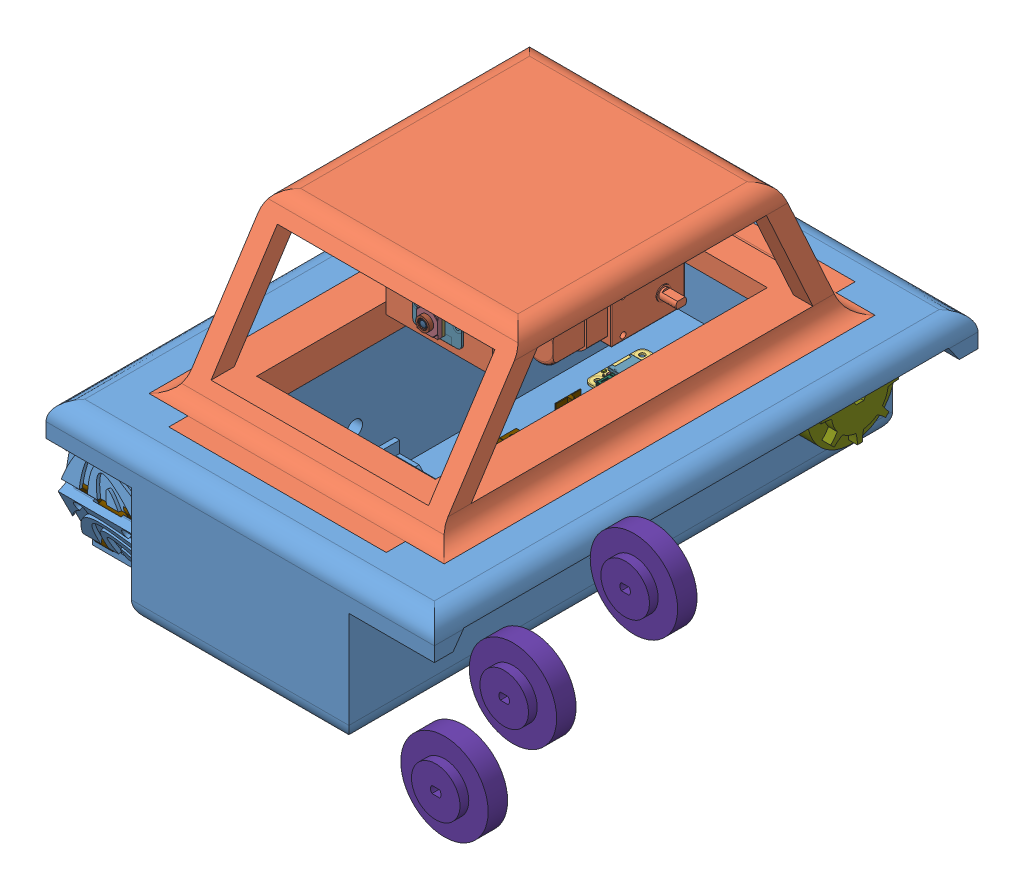
SolidWorks assembly AV_Comp_Mech_1_3_3_TotalAssembly, configuration Default. Lengths in mm.
Overall size (348.43 162.79 404.85).
170 component instances, 37 part files, 41 mates.
Components (placement in the parent):
- AV_Comp_Mech_1_3_2_3_Chassis3_Bot-1: AV_Comp_Mech_1_3_2_3_Chassis3_Bot [Default] at (109.8755 25.442 260.27) size (200 77.5 280)
- AV_Comp_Mech_1_3_1_3_Motors-1: AV_Comp_Mech_1_3_1_3_Motors [Default] at (82.6825 -10.6209 15.27) x (0 1 0) z (-1 0 0) size (22.6 65.53 37.6)
- AV_Comp_Mech_1_3_1_3_Motors-2: AV_Comp_Mech_1_3_1_3_Motors [Default] at (155.8685 -10.6209 15.27) x (0 1 0) z (-1 0 0) size (22.6 65.53 37.6)
- AV_Comp_Mech_1_3_1_2_Pi_Zero-1: AV_Comp_Mech_1_3_1_2_Pi_Zero [Default] at (157.9171 -59.1547 19.3835) size (65 4.45 31.23)
  - Raspberry_pizero_PCB-1: Raspberry_pizero_PCB [Default] at (-51.2564 20.0966 13.0542) size (65 1 30)
  - Micro USB_input_female (short)-SMT-1: Micro USB_input_female (short)-SMT [Default] at (-42.3564 22.3216 26.5042) size (7.98 2.94 5.43)
  - Micro USB_input_female (short)-SMT-2: Micro USB_input_female (short)-SMT [Default] at (-29.7564 22.3216 26.5042) size (7.98 2.94 5.43)
  - 0204 - Capacitor-1: 0204 - Capacitor [Default] at (-62.4121 21.3466 11.2398) size (1 0.5 0.6)
  - 0204 - Capacitor-2: 0204 - Capacitor [Default] at (-62.4121 21.3466 12.2528) size (1 0.5 0.6)
  - 0204 - Capacitor-3: 0204 - Capacitor [Default] at (-61.8122 21.3466 13.3136) size (1 0.5 0.6)
  - 0204 - Capacitor-4: 0204 - Capacitor [Default] at (-61.8122 21.3466 14.2646) size (1 0.5 0.6)
  - 0204 - Capacitor-5: 0204 - Capacitor [Default] at (-61.8122 21.3466 15.241) size (1 0.5 0.6)
  - 0204 - Capacitor-6: 0204 - Capacitor [Default] at (-61.8122 21.3466 16.2144) size (1 0.5 0.6)
  - 0204 - Capacitor-7: 0204 - Capacitor [Default] at (-61.8122 21.3466 17.2416) size (1 0.5 0.6)
  - 0204 - Capacitor-8: 0204 - Capacitor [Default] at (-62.5919 21.3466 20.9695) size (1 0.5 0.6)
  - 0204 - Capacitor-9: 0204 - Capacitor [Default] at (-62.5919 21.3466 21.919) size (1 0.5 0.6)
  - 0204 - Capacitor-10: 0204 - Capacitor [Default] at (-60.4584 21.3466 22.3712) x (0 0 1) z (-1 0 0) size (1 0.5 0.6)
  - 0204 - Capacitor-11: 0204 - Capacitor [Default] at (-60.0807 21.3466 22.3712) x (0 0 -1) z (1 0 0) size (1 0.5 0.6)
  - 0204 - Capacitor-12: 0204 - Capacitor [Default] at (-59.0466 21.3466 22.3712) x (0 0 -1) z (1 0 0) size (1 0.5 0.6)
  - 0204 - Capacitor-13: 0204 - Capacitor [Default] at (-52.6496 21.3466 22.316) x (0 0 1) z (-1 0 0) size (1 0.5 0.6)
  - 0204 - Capacitor-14: 0204 - Capacitor [Default] at (-52.25 21.3466 22.316) x (0 0 -1) z (1 0 0) size (1 0.5 0.6)
  - 0204 - Capacitor-15: 0204 - Capacitor [Default] at (-51.2398 21.3466 22.316) x (0 0 -1) z (1 0 0) size (1 0.5 0.6)
  - 0204 - Capacitor-16: 0204 - Capacitor [Default] at (-49.1841 21.3466 22.316) x (0 0 -1) z (1 0 0) size (1 0.5 0.6)
  - 0204 - Capacitor-17: 0204 - Capacitor [Default] at (-48.1448 21.3466 22.316) x (0 0 -1) z (1 0 0) size (1 0.5 0.6)
  - 0204 - Capacitor-18: 0204 - Capacitor [Default] at (-46.475 21.3466 21.113) size (1 0.5 0.6)
  - 0204 - Capacitor-19: 0204 - Capacitor [Default] at (-45.7322 21.3466 20.0663) size (1 0.5 0.6)
  - 0204 - Capacitor-20: 0204 - Capacitor [Default] at (-45.7322 21.3466 19.0675) size (1 0.5 0.6)
  - 0204 - Capacitor-21: 0204 - Capacitor [Default] at (-45.7322 21.3466 18.1249) size (1 0.5 0.6)
  - 0204 - Capacitor-22: 0204 - Capacitor [Default] at (-45.7322 21.3466 17.1095) size (1 0.5 0.6)
  - 0204 - Capacitor-23: 0204 - Capacitor [Default] at (-46.3457 21.3466 16.1412) size (1 0.5 0.6)
  - 0204 - Capacitor-24: 0204 - Capacitor [Default] at (-46.3457 21.3466 15.1229) size (1 0.5 0.6)
  - 0204 - Capacitor-25: 0204 - Capacitor [Default] at (-46.3457 21.3466 14.0197) size (1 0.5 0.6)
  - 0204 - Capacitor-26: 0204 - Capacitor [Default] at (-46.3457 21.3466 12.9589) size (1 0.5 0.6)
  - 0204 - Capacitor-27: 0204 - Capacitor [Default] at (-43.6156 21.3466 13.1418) size (1 0.5 0.6)
  - 0204 - Capacitor-28: 0204 - Capacitor [Default] at (-43.6156 21.3466 10.1424) size (1 0.5 0.6)
  - 0204 - Capacitor-29: 0204 - Capacitor [Default] at (-48.9117 21.3466 7.6917) size (1 0.5 0.6)
  - 0204 - Capacitor-30: 0204 - Capacitor [Default] at (-55.4926 21.3466 7.2526) x (0 0 -1) z (1 0 0) size (1 0.5 0.6)
  - 0204 - Capacitor-31: 0204 - Capacitor [Default] at (-53.7932 21.3466 7.2526) x (0 0 1) z (-1 0 0) size (1 0.5 0.6)
  - 0204 - Capacitor-32: 0204 - Capacitor [Default] at (-59.8477 21.3466 7.2526) x (0 0 1) z (-1 0 0) size (1 0.5 0.6)
  - 0204- Resistor-15: 0204- Resistor [Default] at (-43.6109 21.4522 15.4193) x (-1 0 0) z (0 -1 0) size (0.99 0.51 0.36)
  - 0204- Resistor-14: 0204- Resistor [Default] at (-43.6109 21.4522 14.4127) x (-1 0 0) z (0 -1 0) size (0.99 0.51 0.36)
  - 0204- Resistor-13: 0204- Resistor [Default] at (-43.6109 21.4522 12.4047) x (-1 0 0) z (0 -1 0) size (0.99 0.51 0.36)
  - 0204- Resistor-4: 0204- Resistor [Default] at (-42.6936 21.4522 18.4076) x (-1 0 0) z (0 -1 0) size (0.99 0.51 0.36)
  - 0204- Resistor-5: 0204- Resistor [Default] at (-39.831 21.4522 18.1462) x (0 0 1) z (0 -1 0) size (0.99 0.51 0.36)
  - 0204- Resistor-7: 0204- Resistor [Default] at (-61.8169 21.4522 19.8533) x (-1 0 0) z (0 -1 0) size (0.99 0.51 0.36)
  - 0204- Resistor-8: 0204- Resistor [Default] at (-61.8169 21.4522 18.5178) x (-1 0 0) z (0 -1 0) size (0.99 0.51 0.36)
  - 0204- Resistor-9: 0204- Resistor [Default] at (-79.148 21.4522 17.7279) x (-1 0 0) z (0 -1 0) size (0.99 0.51 0.36)
  - 0204- Resistor-10: 0204- Resistor [Default] at (-56.0985 21.4522 7.2479) x (0 0 -1) z (0 -1 0) size (0.99 0.51 0.36)
  - 0204- Resistor-11: 0204- Resistor [Default] at (-28.0827 21.4522 9.5819) x (-1 0 0) z (0 -1 0) size (0.99 0.51 0.36)
  - 0204- Resistor-12: 0204- Resistor [Default] at (-21.8613 21.4522 20.9026) x (-1 0 0) z (0 -1 0) size (0.99 0.51 0.36)
  - CAP-0306-1: CAP-0306 [Default] at (-45.8903 21.4966 8.7634) size (1.6 0.8 0.9)
  - CAP-0306-2: CAP-0306 [Default] at (-82.0031 21.4966 19.0464) x (0 0 1) z (-1 0 0) size (1.6 0.8 0.9)
  - Raspberry_pizero_BCM2835 with VC4-2: Raspberry_pizero_BCM2835 with VC4 [Default] at (-54.1608 21.5466 15.1238) x (1 0 0) z (0 0 -1) size (12 0.65 12)
  - Crystal 3.4x2.4mm-1: Crystal 3.4x2.4mm [Default] at (-65.3089 21.0966 19.2633) size (3.2 1 2.4)
  - 0204- Resistor-16: 0204- Resistor [Default] at (-68.4329 21.4522 5.4384) x (0 0 1) z (0 -1 0) size (0.99 0.51 0.36)
  - 0204- Resistor-17: 0204- Resistor [Default] at (-69.7255 21.4522 5.4384) x (0 0 1) z (0 -1 0) size (0.99 0.51 0.36)
  - 0204- Resistor-18: 0204- Resistor [Default] at (-65.0626 21.4522 16.5355) x (1 0 0) z (0 -1 0) size (0.99 0.51 0.36)
  - 32,768 Khz Crystal-1: 32,768 Khz Crystal [Default] at (-60.5154 21.1428 26.5473) x (0.999848 -0.017452 0) z (0 0 1) size (3.4 1.03 1.5)
  - 0805- Capacitor-1: 0805- Capacitor [Default] at (-51.9496 21.9966 5.2384) x (1 0 0) z (0 -1 0) size (2 1.25 0.9)
  - 0805- Capacitor-2: 0805- Capacitor [Default] at (-51.9496 21.9966 7.3589) x (1 0 0) z (0 -1 0) size (2 1.25 0.9)
  - 0805- Capacitor-3: 0805- Capacitor [Default] at (-37.009 21.9966 22.5384) x (0 0 -1) z (0 -1 0) size (2 1.25 0.9)
  - 0805- Capacitor-4: 0805- Capacitor [Default] at (-29.8247 21.9966 13.3538) x (0 0 1) z (0 -1 0) size (2 1.25 0.9)
  - 0805- Capacitor-5: 0805- Capacitor [Default] at (-27.9052 21.9966 13.3538) x (0 0 -1) z (0 -1 0) size (2 1.25 0.9)
  - 0805- Capacitor-6: 0805- Capacitor [Default] at (-22.8003 21.9966 13.3538) x (0 0 -1) z (0 -1 0) size (2 1.25 0.9)
  - 0805- Capacitor-7: 0805- Capacitor [Default] at (-20.9924 21.9966 13.3538) x (0 0 -1) z (0 -1 0) size (2 1.25 0.9)
  - 0204- Resistor-19: 0204- Resistor [Default] at (-48.8769 21.4522 23.8207) x (1 0 0) z (0 -1 0) size (0.99 0.51 0.36)
  - 0204- Resistor-20: 0204- Resistor [Default] at (-52.4165 21.4522 24.0419) x (1 0 0) z (0 -1 0) size (0.99 0.51 0.36)
  - 0204 - Capacitor-33: 0204 - Capacitor [Default] at (-47.1199 21.3466 23.926) x (0 0 1) z (-1 0 0) size (1 0.5 0.6)
  - 0204 - Capacitor Brown-34: 0204 - Capacitor Brown [Default] at (-57.5817 21.3466 26.803) size (1 0.5 0.6)
  - 0204 - Capacitor Brown-35: 0204 - Capacitor Brown [Default] at (-64.0312 21.3466 26.8794) size (1 0.5 0.6)
  - 0204 - Capacitor Brown-36: 0204 - Capacitor Brown [Default] at (-46.3457 21.3466 12.214) size (1 0.5 0.6)
  - 0204 - Capacitor Brown-37: 0204 - Capacitor Brown [Default] at (-46.3457 21.3466 11.0963) size (1 0.5 0.6)
  - 0204 - Capacitor Brown-38: 0204 - Capacitor Brown [Default] at (-46.3457 21.3466 10.1566) size (1 0.5 0.6)
  - 0204 - Capacitor Brown-39: 0204 - Capacitor Brown [Default] at (-43.6156 21.3466 11.1151) size (1 0.5 0.6)
  - 0204 - Capacitor Brown-40: 0204 - Capacitor Brown [Default] at (-28.0874 21.3466 10.3236) size (1 0.5 0.6)
  - 0204 - Capacitor Brown-41: 0204 - Capacitor Brown [Default] at (-80.6197 21.3466 20.6997) size (1 0.5 0.6)
  - 0204- Resistor-21: 0204- Resistor [Default] at (-78.9105 21.4522 21.1554) x (1 0 0) z (0 -1 0) size (0.99 0.51 0.36)
  - 6-Pin SOT-1: 6-Pin SOT [Default] at (-79.714 21.0966 19.2138) x (0 0 1) z (0 1 0) size (1.5 1.84 0.95)
  - micro sd molex-1: micro sd molex [Default] at (-74.7768 21.6766 -33.0961) x (0 0 1) z (0 1 0) size (11.95 11.4 1.45)
  - hdmi type C-1: hdmi type C [Default] at (-71.3564 22.9466 28.6542) size (12.9 4.05 7.7)
  - Voltage Regulator 3x3mm 12-Pin-1: Voltage Regulator 3x3mm 12-Pin [Default] at (-23.6842 21.0966 12.6105) x (1 0 0) z (0 1 0) size (3 4.1 1.2)
  - 1210 inductor-1: 1210 inductor [Default] at (-46.4963 21.0916 6.3909) x (0 0 1) z (0 1 0) size (3.26 2.86 0.75)
  - 1210 inductor-2: 1210 inductor [Default] at (-22.7405 21.0916 9.2394) x (1 0 0) z (0 1 0) size (3.26 2.86 0.75)
  - 1210 inductor-3: 1210 inductor [Default] at (-28.2854 21.0916 17.6682) x (1 0 0) z (0 1 0) size (3.26 2.86 0.75)
  - 0204 - Capacitor-34: 0204 - Capacitor [Default] at (-48.9117 21.3466 6.5273) size (1 0.5 0.6)
- AV_Comp_Mech_1_3_1_4_L298N_Motor_Driver-1: AV_Comp_Mech_1_3_1_4_L298N_Motor_Driver [Default] at (109.7296 -39.058 96.096) size (50 22 50)
- AV_Comp_Mech_1_3_1_6_18650_Battery_Pack-1: AV_Comp_Mech_1_3_1_6_18650_Battery_Pack [Default] at (110.2176 -39.058 257.7831) x (1 0 0) z (0 1 0) size (77.98 59.63 24.74)
- AV_Comp_Mech_1_3_2_3_Chassis3_Top-1: AV_Comp_Mech_1_3_2_3_Chassis3_Top [Default] at (109.8685 25.442 267.7659) size (152 78.5 241.5)
- AV_Comp_Mech_1_3_1_5_Pi_Cam-1: AV_Comp_Mech_1_3_1_5_Pi_Cam [Default] at (109.8685 64.3515 159.8859) size (25 28.06 11.35)
  - AV_Comp_Mech_1_3_1_6_Pi_Cam.step-1: AV_Comp_Mech_1_3_1_6_Pi_Cam.step [Default] at origin size (25 28.06 11.35)
    - Rear Components.step-1: Rear Components.step [Default] at origin size (20.8 26.49 2.7)
      - sfw15r3ste1lf.step-1: sfw15r3ste1lf.step [Default] at (-17.3 -10.562 -4.82) x (1 0 0) z (0 -1 0) size (20.8 2.7 9.5)
      - Rear Components-0.step-1: Rear Components-0.step [Default] at origin size (3 1.5 1)
      - Rear Components-1.step-1: Rear Components-1.step [Default] at origin size (5 3 1)
      - Rear Components-2.step-1: Rear Components-2.step [Default] at origin size (3 1.5 1)
      - Rear Components-3.step-1: Rear Components-3.step [Default] at origin size (3 1.5 1)
      - Rear Components-4.step-1: Rear Components-4.step [Default] at origin size (2 3 1)
    - Sony IMX708.step-1: Sony IMX708.step [Default] at origin size (10.83 18.1 7.53)
      - Sensor.step-1: Sensor.step [Default] at origin size (8.9 16.17 1.26)
      - Lens.step-1: Lens.step [Default] at origin size (3.5 3.5 6.28)
      - Ring.step-1: Ring.step [Default] at origin size (7 7 6.25)
      - Mount.step-1: Mount.step [Default] at origin size (10.8 10.8 1.5)
      - Housing.step-1: Housing.step [Default] at origin size (10.8 10.8 2.5)
    - Board.step-1: Board.step [Default] at origin size (25 23.86 1.12)
    - Camera Moudule 3.step-1: Camera Moudule 3.step [Default] at origin size (6.95 6.95 1.12)
- AV_Comp_Mech_1_1_7_DriverWheel-1: AV_Comp_Mech_1_1_7_DriverWheel [Default] at (54.4825 -10.6348 15.2784) x (0 0 -1) z (0 1 0) size (45 19 45)
- AV_Comp_Mech_1_1_7_DriverWheel-3: AV_Comp_Mech_1_1_7_DriverWheel [Default] at (165.2685 -7.0071 15.506) x (0 0 1) z (0 1 0) size (45 19 45)
- AV_Comp_Mech_1_1_8_GroundWheel-1: AV_Comp_Mech_1_1_8_GroundWheel [Default] at (304.5966 88.8972 237.7053) size (45 45 19)
- AV_Comp_Mech_1_1_8_GroundWheel-2: AV_Comp_Mech_1_1_8_GroundWheel [Default] at (335.4529 78.1076 366.1173) size (45 45 19)
- AV_Comp_Mech_1_1_8_GroundWheel-3: AV_Comp_Mech_1_1_8_GroundWheel [Default] at (281.9522 48.6042 277.353) size (45 45 19)
- AV_Comp_Mech_1_1_8_GroundWheel-4: AV_Comp_Mech_1_1_8_GroundWheel [Default] at (29.3228 -10.6209 85.27) x (0 0 -1) z (1 0 0) size (45 45 19)
- AV_Comp_Mech_1_1_8_GroundWheel-5: AV_Comp_Mech_1_1_8_GroundWheel [Default] at (34.8755 -10.6209 225.27) x (0 -0.453362 -0.891326) z (1 0 0) size (45 45 19)
- AV_Comp_Mech_1_1_8_GroundWheel-6: AV_Comp_Mech_1_1_8_GroundWheel [Default] at (34.8755 -10.6209 155.27) x (0 -0.068416 -0.997657) z (1 0 0) size (45 45 19)
- AV_Comp_Mech_1_1_9_WholeTrack-1: AV_Comp_Mech_1_1_9_WholeTrack [Default] at (17.1763 -59.9641 -22.1521) x (0 0 -1) z (1 0 0) size (225.46 19.36 44.35)
  - AV_Comp_Mech_1_1_6_TrackAssembly-1: AV_Comp_Mech_1_1_6_TrackAssembly [Default] at (-66.8469 2.2745 -10.8813) size (35.18 19.36 44)
    - AV_Comp_Mech_1_1_3_TracksV3-1: AV_Comp_Mech_1_1_3_TracksV3 [Default] at (9.2421 14.1316 25.58) size (35.18 14.36 35)
    - AV_Comp_Mech_1_1_5_OuterTrack_TPU_2-1: AV_Comp_Mech_1_1_5_OuterTrack_TPU_2 [Default] at (12.2777 11.1316 25.5805) x (1 0 0) z (0 1 0) size (28.18 44 9)
  - AV_Comp_Mech_1_1_3_TracksV3-1: AV_Comp_Mech_1_1_3_TracksV3 [Default] at (-84.787 16.4061 15.0487) size (35.18 14.36 35)
  - AV_Comp_Mech_1_1_5_OuterTrack_TPU_2-1: AV_Comp_Mech_1_1_5_OuterTrack_TPU_2 [Default] at (-81.7514 13.4061 15.0492) x (1 0 0) z (0 1 0) size (28.18 44 9)
  - AV_Comp_Mech_1_1_5_OuterTrack_TPU_2-3: AV_Comp_Mech_1_1_5_OuterTrack_TPU_2 [Default] at (-136.1157 13.4061 15.0492) x (1 0 0) z (0 1 0) size (28.18 44 9)
  - AV_Comp_Mech_1_1_3_TracksV3-3: AV_Comp_Mech_1_1_3_TracksV3 [Default] at (-139.1513 16.4061 15.0487) size (35.18 14.36 35)
  - AV_Comp_Mech_1_1_6_TrackAssembly-3: AV_Comp_Mech_1_1_6_TrackAssembly [Default] at (-121.2112 2.2745 -10.8813) size (35.18 19.36 44)
    - AV_Comp_Mech_1_1_3_TracksV3-1: AV_Comp_Mech_1_1_3_TracksV3 [Default] at (9.2421 14.1316 25.58) size (35.18 14.36 35)
    - AV_Comp_Mech_1_1_5_OuterTrack_TPU_2-1: AV_Comp_Mech_1_1_5_OuterTrack_TPU_2 [Default] at (12.2777 11.1316 25.5805) x (1 0 0) z (0 1 0) size (28.18 44 9)
  - AV_Comp_Mech_1_1_5_OuterTrack_TPU_2-4: AV_Comp_Mech_1_1_5_OuterTrack_TPU_2 [Default] at (-190.48 13.4061 15.0492) x (1 0 0) z (0 1 0) size (28.18 44 9)
  - AV_Comp_Mech_1_1_5_OuterTrack_TPU_2-5: AV_Comp_Mech_1_1_5_OuterTrack_TPU_2 [Default] at (-244.8444 13.4061 15.0492) x (1 0 0) z (0 1 0) size (28.18 44 9)
  - AV_Comp_Mech_1_1_3_TracksV3-4: AV_Comp_Mech_1_1_3_TracksV3 [Default] at (-247.8799 16.4061 15.0487) size (35.18 14.36 35)
  - AV_Comp_Mech_1_1_6_TrackAssembly-4: AV_Comp_Mech_1_1_6_TrackAssembly [Default] at (-229.9399 2.2745 -10.8813) size (35.18 19.36 44)
    - AV_Comp_Mech_1_1_3_TracksV3-1: AV_Comp_Mech_1_1_3_TracksV3 [Default] at (9.2421 14.1316 25.58) size (35.18 14.36 35)
    - AV_Comp_Mech_1_1_5_OuterTrack_TPU_2-1: AV_Comp_Mech_1_1_5_OuterTrack_TPU_2 [Default] at (12.2777 11.1316 25.5805) x (1 0 0) z (0 1 0) size (28.18 44 9)
  - AV_Comp_Mech_1_1_3_TracksV3-5: AV_Comp_Mech_1_1_3_TracksV3 [Default] at (-193.5156 16.4061 15.0487) size (35.18 14.36 35)
  - AV_Comp_Mech_1_1_6_TrackAssembly-5: AV_Comp_Mech_1_1_6_TrackAssembly [Default] at (-175.5755 2.2745 -10.8813) size (35.18 19.36 44)
    - AV_Comp_Mech_1_1_3_TracksV3-1: AV_Comp_Mech_1_1_3_TracksV3 [Default] at (9.2421 14.1316 25.58) size (35.18 14.36 35)
    - AV_Comp_Mech_1_1_5_OuterTrack_TPU_2-1: AV_Comp_Mech_1_1_5_OuterTrack_TPU_2 [Default] at (12.2777 11.1316 25.5805) x (1 0 0) z (0 1 0) size (28.18 44 9)
- AV_Comp_Mech_1_1_9_WholeTrack-4: AV_Comp_Mech_1_1_9_WholeTrack [Default] at (16.8263 29.7223 277.0215) x (0 0 1) z (1 0 0) size (225.46 19.36 44.35)
  - AV_Comp_Mech_1_1_6_TrackAssembly-1: AV_Comp_Mech_1_1_6_TrackAssembly [Default] at (-66.8469 2.2745 -10.8813) size (35.18 19.36 44)
    - AV_Comp_Mech_1_1_3_TracksV3-1: AV_Comp_Mech_1_1_3_TracksV3 [Default] at (9.2421 14.1316 25.58) size (35.18 14.36 35)
    - AV_Comp_Mech_1_1_5_OuterTrack_TPU_2-1: AV_Comp_Mech_1_1_5_OuterTrack_TPU_2 [Default] at (12.2777 11.1316 25.5805) x (1 0 0) z (0 1 0) size (28.18 44 9)
  - AV_Comp_Mech_1_1_3_TracksV3-1: AV_Comp_Mech_1_1_3_TracksV3 [Default] at (-84.787 16.4061 15.0487) size (35.18 14.36 35)
  - AV_Comp_Mech_1_1_5_OuterTrack_TPU_2-1: AV_Comp_Mech_1_1_5_OuterTrack_TPU_2 [Default] at (-81.7514 13.4061 15.0492) x (1 0 0) z (0 1 0) size (28.18 44 9)
  - AV_Comp_Mech_1_1_5_OuterTrack_TPU_2-3: AV_Comp_Mech_1_1_5_OuterTrack_TPU_2 [Default] at (-136.1157 13.4061 15.0492) x (1 0 0) z (0 1 0) size (28.18 44 9)
  - AV_Comp_Mech_1_1_3_TracksV3-3: AV_Comp_Mech_1_1_3_TracksV3 [Default] at (-139.1513 16.4061 15.0487) size (35.18 14.36 35)
  - AV_Comp_Mech_1_1_6_TrackAssembly-3: AV_Comp_Mech_1_1_6_TrackAssembly [Default] at (-121.2112 2.2745 -10.8813) size (35.18 19.36 44)
    - AV_Comp_Mech_1_1_3_TracksV3-1: AV_Comp_Mech_1_1_3_TracksV3 [Default] at (9.2421 14.1316 25.58) size (35.18 14.36 35)
    - AV_Comp_Mech_1_1_5_OuterTrack_TPU_2-1: AV_Comp_Mech_1_1_5_OuterTrack_TPU_2 [Default] at (12.2777 11.1316 25.5805) x (1 0 0) z (0 1 0) size (28.18 44 9)
  - AV_Comp_Mech_1_1_5_OuterTrack_TPU_2-4: AV_Comp_Mech_1_1_5_OuterTrack_TPU_2 [Default] at (-190.48 13.4061 15.0492) x (1 0 0) z (0 1 0) size (28.18 44 9)
  - AV_Comp_Mech_1_1_5_OuterTrack_TPU_2-5: AV_Comp_Mech_1_1_5_OuterTrack_TPU_2 [Default] at (-244.8444 13.4061 15.0492) x (1 0 0) z (0 1 0) size (28.18 44 9)
  - AV_Comp_Mech_1_1_3_TracksV3-4: AV_Comp_Mech_1_1_3_TracksV3 [Default] at (-247.8799 16.4061 15.0487) size (35.18 14.36 35)
  - AV_Comp_Mech_1_1_6_TrackAssembly-4: AV_Comp_Mech_1_1_6_TrackAssembly [Default] at (-229.9399 2.2745 -10.8813) size (35.18 19.36 44)
    - AV_Comp_Mech_1_1_3_TracksV3-1: AV_Comp_Mech_1_1_3_TracksV3 [Default] at (9.2421 14.1316 25.58) size (35.18 14.36 35)
    - AV_Comp_Mech_1_1_5_OuterTrack_TPU_2-1: AV_Comp_Mech_1_1_5_OuterTrack_TPU_2 [Default] at (12.2777 11.1316 25.5805) x (1 0 0) z (0 1 0) size (28.18 44 9)
  - AV_Comp_Mech_1_1_3_TracksV3-5: AV_Comp_Mech_1_1_3_TracksV3 [Default] at (-193.5156 16.4061 15.0487) size (35.18 14.36 35)
  - AV_Comp_Mech_1_1_6_TrackAssembly-5: AV_Comp_Mech_1_1_6_TrackAssembly [Default] at (-175.5755 2.2745 -10.8813) size (35.18 19.36 44)
    - AV_Comp_Mech_1_1_3_TracksV3-1: AV_Comp_Mech_1_1_3_TracksV3 [Default] at (9.2421 14.1316 25.58) size (35.18 14.36 35)
    - AV_Comp_Mech_1_1_5_OuterTrack_TPU_2-1: AV_Comp_Mech_1_1_5_OuterTrack_TPU_2 [Default] at (12.2777 11.1316 25.5805) x (1 0 0) z (0 1 0) size (28.18 44 9)
- AV_Comp_Mech_1_1_6_TrackAssembly-2: AV_Comp_Mech_1_1_6_TrackAssembly [Default] at (6.295 -56.7071 9.1166) x (0 0.474367 -0.880327) z (1 0 0) size (35.18 19.36 44)
  - AV_Comp_Mech_1_1_3_TracksV3-1: AV_Comp_Mech_1_1_3_TracksV3 [Default] at (9.2421 14.1316 25.58) size (35.18 14.36 35)
  - AV_Comp_Mech_1_1_5_OuterTrack_TPU_2-1: AV_Comp_Mech_1_1_5_OuterTrack_TPU_2 [Default] at (12.2777 11.1316 25.5805) x (1 0 0) z (0 1 0) size (28.18 44 9)
- AV_Comp_Mech_1_1_6_TrackAssembly-3: AV_Comp_Mech_1_1_6_TrackAssembly [Default] at (6.295 -25.9515 -25.861) x (0 0.973693 0.227866) z (1 0 0) size (35.18 19.36 44)
  - AV_Comp_Mech_1_1_3_TracksV3-1: AV_Comp_Mech_1_1_3_TracksV3 [Default] at (9.2421 14.1316 25.58) size (35.18 14.36 35)
  - AV_Comp_Mech_1_1_5_OuterTrack_TPU_2-1: AV_Comp_Mech_1_1_5_OuterTrack_TPU_2 [Default] at (12.2777 11.1316 25.5805) x (1 0 0) z (0 1 0) size (28.18 44 9)
- AV_Comp_Mech_1_1_6_TrackAssembly-4: AV_Comp_Mech_1_1_6_TrackAssembly [Default] at (6.295 13.3691 -11.7683) x (0 0.423545 0.905875) z (1 0 0) size (35.18 19.36 44)
  - AV_Comp_Mech_1_1_3_TracksV3-1: AV_Comp_Mech_1_1_3_TracksV3 [Default] at (9.2421 14.1316 25.58) size (35.18 14.36 35)
  - AV_Comp_Mech_1_1_5_OuterTrack_TPU_2-1: AV_Comp_Mech_1_1_5_OuterTrack_TPU_2 [Default] at (12.2777 11.1316 25.5805) x (1 0 0) z (0 1 0) size (28.18 44 9)
- AV_Comp_Mech_1_1_6_TrackAssembly-5: AV_Comp_Mech_1_1_6_TrackAssembly [Default] at (6.295 15.9359 255.9469) x (0 -0.979941 0.199286) z (1 0 0) size (35.18 19.36 44)
  - AV_Comp_Mech_1_1_3_TracksV3-1: AV_Comp_Mech_1_1_3_TracksV3 [Default] at (9.2421 14.1316 25.58) size (35.18 14.36 35)
  - AV_Comp_Mech_1_1_5_OuterTrack_TPU_2-1: AV_Comp_Mech_1_1_5_OuterTrack_TPU_2 [Default] at (12.2777 11.1316 25.5805) x (1 0 0) z (0 1 0) size (28.18 44 9)
- AV_Comp_Mech_1_1_6_TrackAssembly-6: AV_Comp_Mech_1_1_6_TrackAssembly [Default] at (6.295 -22.0693 261.319) x (0 -0.891663 -0.4527) z (1 0 0) size (35.18 19.36 44)
  - AV_Comp_Mech_1_1_3_TracksV3-1: AV_Comp_Mech_1_1_3_TracksV3 [Default] at (9.2421 14.1316 25.58) size (35.18 14.36 35)
  - AV_Comp_Mech_1_1_5_OuterTrack_TPU_2-1: AV_Comp_Mech_1_1_5_OuterTrack_TPU_2 [Default] at (12.2777 11.1316 25.5805) x (1 0 0) z (0 1 0) size (28.18 44 9)
Mates (geometry in assembly coordinates):
- Concentric1: concentric anti-aligned: cylinder of AV_Comp_Mech_1_3_2_3_Chassis3_Bot-1 through (177.1892 -10.6209 15.27) axis (-1 0 0) radius 4; cylinder of AV_Comp_Mech_1_3_1_3_Motors-1 through (63.3825 -10.6209 15.27) axis (1 0 0) radius 3.6
- Coincident1: coincident anti-aligned: plane of AV_Comp_Mech_1_3_2_3_Chassis3_Bot-1 through (63.8825 -39.058 260.27) normal (1 0 0); plane of AV_Comp_Mech_1_3_1_3_Motors-1 through (63.8825 -10.6209 15.27) normal (-1 0 0)
- Concentric2: concentric aligned: cylinder of AV_Comp_Mech_1_3_2_3_Chassis3_Bot-1 through (177.1892 -10.6209 15.27) axis (-1 0 0) radius 4; cylinder of AV_Comp_Mech_1_3_1_3_Motors-2 through (156.3685 -10.6209 15.27) axis (-1 0 0) radius 3.6
- Coincident2: coincident anti-aligned: plane of AV_Comp_Mech_1_3_2_3_Chassis3_Bot-1 through (155.8685 -39.058 260.27) normal (-1 0 0); plane of AV_Comp_Mech_1_3_1_3_Motors-2 through (155.8685 -10.6209 15.27) normal (1 0 0)
- Parallel1: parallel aligned: plane of AV_Comp_Mech_1_3_2_3_Chassis3_Bot-1 through (109.8755 -39.058 260.27) normal (0 1 0); plane of AV_Comp_Mech_1_3_1_3_Motors-1 through (63.8825 0.6291 41.87) normal (0 1 0)
- Parallel2: parallel aligned: plane of AV_Comp_Mech_1_3_2_3_Chassis3_Bot-1 through (109.8755 -39.058 260.27) normal (0 1 0); plane of AV_Comp_Mech_1_3_1_3_Motors-2 through (137.0685 0.6291 41.87) normal (0 1 0)
- Coincident6: coincident anti-aligned: plane of AV_Comp_Mech_1_3_2_3_Chassis3_Bot-1 through (109.8755 -39.058 260.27) normal (0 1 0); plane of AV_Comp_Mech_1_3_1_2_Pi_Zero-1/Raspberry_pizero_PCB-1 through (77.1607 -39.058 20.4378) normal (0 -1 0)
- Coincident7: coincident anti-aligned: plane of AV_Comp_Mech_1_3_2_3_Chassis3_Bot-1 through (109.8755 -39.058 260.27) normal (0 1 0); plane of AV_Comp_Mech_1_3_1_4_L298N_Motor_Driver-1 through (109.7296 -39.058 96.096) normal (0 -1 0)
- Coincident8: coincident anti-aligned: plane of AV_Comp_Mech_1_3_2_3_Chassis3_Bot-1 through (109.8755 -39.058 260.27) normal (0 1 0); plane of AV_Comp_Mech_1_3_1_6_18650_Battery_Pack-1 through (110.2176 -39.058 171.7831) normal (0 -1 0)
- Parallel3: parallel anti-aligned: plane of AV_Comp_Mech_1_3_2_3_Chassis3_Bot-1 through (155.8685 -39.058 260.27) normal (-1 0 0); plane of AV_Comp_Mech_1_3_1_6_18650_Battery_Pack-1 through (149.2076 -39.058 141.9681) normal (1 0 0)
- Coincident10: coincident aligned: circle of AV_Comp_Mech_1_3_2_3_Chassis3_Top-1; circle of AV_Comp_Mech_1_3_1_5_Pi_Cam-1/AV_Comp_Mech_1_3_1_6_Pi_Cam.step-1/Board.step-1
- Coincident11: coincident anti-aligned: plane of AV_Comp_Mech_1_3_2_3_Chassis3_Bot-1 through (109.8755 21.942 260.27) normal (0 1 0); plane of AV_Comp_Mech_1_3_2_3_Chassis3_Top-1 through (109.8685 21.942 267.7659) normal (0 -1 0)
- Coincident12: coincident anti-aligned: plane of AV_Comp_Mech_1_3_2_3_Chassis3_Bot-1 through (9.8755 27.942 -19.73) normal (0 1 0); plane of AV_Comp_Mech_1_3_2_3_Chassis3_Top-1 through (5.021 27.942 -12.2341) normal (0 -1 0)
- Coincident13: coincident anti-aligned: plane of AV_Comp_Mech_1_3_2_3_Chassis3_Bot-1 through (165.8685 21.942 260.27) normal (-1 0 0); plane of AV_Comp_Mech_1_3_2_3_Chassis3_Top-1 through (165.8685 21.942 267.7659) normal (1 0 0)
- Coincident14: coincident anti-aligned: plane of AV_Comp_Mech_1_3_2_3_Chassis3_Bot-1 through (109.8755 21.942 241.0111) normal (0 0 -1); plane of AV_Comp_Mech_1_3_2_3_Chassis3_Top-1 through (109.8685 21.942 241.0111) normal (0 0 1)
- Coincident15: coincident anti-aligned: line of AV_Comp_Mech_1_3_1_3_Motors-1 through (54.4825 -8.8209 17.2824) axis (0 0 -1); line of AV_Comp_Mech_1_1_7_DriverWheel-1 through (54.4825 -8.8209 13.2784) axis (0 0 1)
- Parallel4: parallel anti-aligned: plane of AV_Comp_Mech_1_3_2_3_Chassis3_Bot-1 through (53.8755 -49.558 -19.73) normal (-1 0 0); plane of AV_Comp_Mech_1_1_7_DriverWheel-1 through (54.4825 -10.6348 15.2784) normal (1 0 0)
- Coincident19: coincident anti-aligned: line of AV_Comp_Mech_1_3_1_3_Motors-2 through (165.2685 -8.8209 17.2824) axis (0 0 -1); line of AV_Comp_Mech_1_1_7_DriverWheel-3 through (165.2685 -8.8209 13.506) axis (0 0 1)
- Parallel6: parallel anti-aligned: plane of AV_Comp_Mech_1_3_2_3_Chassis3_Bot-1 through (165.8755 -49.558 -19.73) normal (1 0 0); plane of AV_Comp_Mech_1_1_7_DriverWheel-3 through (165.2685 -7.0071 15.506) normal (-1 0 0)
- Coincident20: coincident anti-aligned: plane of AV_Comp_Mech_1_3_2_3_Chassis3_Bot-1 through (53.8755 -49.558 -19.73) normal (-1 0 0); plane of AV_Comp_Mech_1_1_9_WholeTrack-1/AV_Comp_Mech_1_1_6_TrackAssembly-3/AV_Comp_Mech_1_1_5_OuterTrack_TPU_2-1 through (53.8755 -48.558 100.8714) normal (1 0 0)
- Parallel7: parallel aligned: plane of AV_Comp_Mech_1_3_2_3_Chassis3_Bot-1 through (9.8755 -49.558 -19.73) normal (0 -1 0); plane of AV_Comp_Mech_1_1_9_WholeTrack-1/AV_Comp_Mech_1_1_5_OuterTrack_TPU_2-5 through (32.2255 -48.558 222.6922) normal (0 -1 0)
- Coincident21: coincident anti-aligned: line of AV_Comp_Mech_1_3_2_3_Chassis3_Bot-1 through (53.8755 -39.558 -19.73) axis (0 0 1); line of AV_Comp_Mech_1_1_9_WholeTrack-1/AV_Comp_Mech_1_1_6_TrackAssembly-1/AV_Comp_Mech_1_1_5_OuterTrack_TPU_2-1 through (53.8755 -39.558 46.5071) axis (0 0 -1)
- Coincident25: coincident aligned: line of AV_Comp_Mech_1_3_2_3_Chassis3_Bot-1 through (53.8755 18.3162 -4.5033) axis (0 0 1); line of AV_Comp_Mech_1_1_9_WholeTrack-4/AV_Comp_Mech_1_1_5_OuterTrack_TPU_2-3 through (53.8755 18.3162 140.9046) axis (0 0 1)
- Coincident26: coincident anti-aligned: plane of AV_Comp_Mech_1_3_2_3_Chassis3_Bot-1 through (53.8755 18.3162 260.27) normal (0 -1 0); plane of AV_Comp_Mech_1_1_9_WholeTrack-4/AV_Comp_Mech_1_1_5_OuterTrack_TPU_2-3 through (31.8755 18.3162 140.9058) normal (0 1 0)
- Coincident29: coincident anti-aligned: line of AV_Comp_Mech_1_1_9_WholeTrack-1/AV_Comp_Mech_1_1_6_TrackAssembly-1/AV_Comp_Mech_1_1_3_TracksV3-1 through (24.8255 -40.558 15.2619) axis (1 0 0); line of AV_Comp_Mech_1_1_6_TrackAssembly-2/AV_Comp_Mech_1_1_3_TracksV3-1 through (39.4755 -40.558 15.2619) axis (-1 0 0)
- Coincident30: coincident anti-aligned: plane of AV_Comp_Mech_1_3_2_3_Chassis3_Bot-1 through (53.8755 -49.558 -19.73) normal (-1 0 0); plane of AV_Comp_Mech_1_1_6_TrackAssembly-2/AV_Comp_Mech_1_1_5_OuterTrack_TPU_2-1 through (53.8755 -49.528 15.0438) normal (1 0 0)
- Coincident31: coincident anti-aligned: line of AV_Comp_Mech_1_1_6_TrackAssembly-2/AV_Comp_Mech_1_1_3_TracksV3-1 through (24.8255 -27.6637 -8.6673) axis (1 0 0); line of AV_Comp_Mech_1_1_6_TrackAssembly-3/AV_Comp_Mech_1_1_3_TracksV3-1 through (39.4755 -27.6637 -8.6673) axis (-1 0 0)
- Coincident32: coincident anti-aligned: plane of AV_Comp_Mech_1_3_2_3_Chassis3_Bot-1 through (53.8755 -49.558 -19.73) normal (-1 0 0); plane of AV_Comp_Mech_1_1_6_TrackAssembly-3/AV_Comp_Mech_1_1_5_OuterTrack_TPU_2-1 through (53.8755 -29.797 -17.3827) normal (1 0 0)
- Coincident33: coincident anti-aligned: line of AV_Comp_Mech_1_1_6_TrackAssembly-3/AV_Comp_Mech_1_1_3_TracksV3-1 through (24.8255 -1.1966 -2.4734) axis (1 0 0); line of AV_Comp_Mech_1_1_6_TrackAssembly-4/AV_Comp_Mech_1_1_3_TracksV3-1 through (39.4755 -1.1966 -2.4734) axis (-1 0 0)
- Coincident34: coincident anti-aligned: plane of AV_Comp_Mech_1_3_2_3_Chassis3_Bot-1 through (53.8755 -49.558 -19.73) normal (-1 0 0); plane of AV_Comp_Mech_1_1_6_TrackAssembly-4/AV_Comp_Mech_1_1_5_OuterTrack_TPU_2-1 through (53.8755 4.3295 -9.5424) normal (1 0 0)
- Coincident35: coincident anti-aligned: line of AV_Comp_Mech_1_1_9_WholeTrack-4/AV_Comp_Mech_1_1_3_TracksV3-4 through (39.4755 10.3162 22.1502) axis (-1 0 0); line of AV_Comp_Mech_1_1_6_TrackAssembly-4/AV_Comp_Mech_1_1_3_TracksV3-1 through (24.8255 10.3162 22.1502) axis (1 0 0)
- Coincident36: coincident anti-aligned: line of AV_Comp_Mech_1_1_9_WholeTrack-4/AV_Comp_Mech_1_1_6_TrackAssembly-1/AV_Comp_Mech_1_1_3_TracksV3-1 through (24.4755 10.3162 239.6075) axis (1 0 0); line of AV_Comp_Mech_1_1_6_TrackAssembly-5/AV_Comp_Mech_1_1_3_TracksV3-1 through (39.4755 10.3162 239.6075) axis (-1 0 0)
- Coincident37: coincident anti-aligned: plane of AV_Comp_Mech_1_3_2_3_Chassis3_Bot-1 through (53.8755 -49.558 -19.73) normal (-1 0 0); plane of AV_Comp_Mech_1_1_6_TrackAssembly-5/AV_Comp_Mech_1_1_5_OuterTrack_TPU_2-1 through (53.8755 15.8921 246.6373) normal (1 0 0)
- Coincident38: coincident anti-aligned: plane of AV_Comp_Mech_1_3_2_3_Chassis3_Bot-1 through (53.8755 -49.558 -19.73) normal (-1 0 0); plane of AV_Comp_Mech_1_1_6_TrackAssembly-6/AV_Comp_Mech_1_1_5_OuterTrack_TPU_2-1 through (53.8755 -16.3194 253.9972) normal (1 0 0)
- Coincident39: coincident anti-aligned: line of AV_Comp_Mech_1_1_6_TrackAssembly-5/AV_Comp_Mech_1_1_3_TracksV3-1 through (24.8255 -16.3207 245.0245) axis (1 0 0); line of AV_Comp_Mech_1_1_6_TrackAssembly-6/AV_Comp_Mech_1_1_3_TracksV3-1 through (39.4755 -16.3207 245.0245) axis (-1 0 0)
- Coincident40: coincident anti-aligned: line of AV_Comp_Mech_1_1_9_WholeTrack-1/AV_Comp_Mech_1_1_3_TracksV3-4 through (39.8255 -40.558 232.7192) axis (-1 0 0); line of AV_Comp_Mech_1_1_6_TrackAssembly-6/AV_Comp_Mech_1_1_3_TracksV3-1 through (24.8255 -40.558 232.7192) axis (1 0 0)
- Concentric3: concentric anti-aligned: circle of AV_Comp_Mech_1_3_2_3_Chassis3_Bot-1; circle of AV_Comp_Mech_1_1_8_GroundWheel-4
- Concentric4: concentric anti-aligned: circle of AV_Comp_Mech_1_3_2_3_Chassis3_Bot-1; circle of AV_Comp_Mech_1_1_8_GroundWheel-6
- Coincident41: coincident anti-aligned: plane of AV_Comp_Mech_1_3_2_3_Chassis3_Bot-1 through (53.8755 -49.558 -19.73) normal (-1 0 0); plane of AV_Comp_Mech_1_1_8_GroundWheel-6 through (53.8755 -10.6698 155.2733) normal (1 0 0)
- Concentric5: concentric anti-aligned: circle of AV_Comp_Mech_1_3_2_3_Chassis3_Bot-1; circle of AV_Comp_Mech_1_1_8_GroundWheel-5
- Coincident42: coincident anti-aligned: plane of AV_Comp_Mech_1_3_2_3_Chassis3_Bot-1 through (53.8755 -49.558 -19.73) normal (-1 0 0); plane of AV_Comp_Mech_1_1_8_GroundWheel-5 through (53.8755 -10.6646 225.2922) normal (1 0 0)
